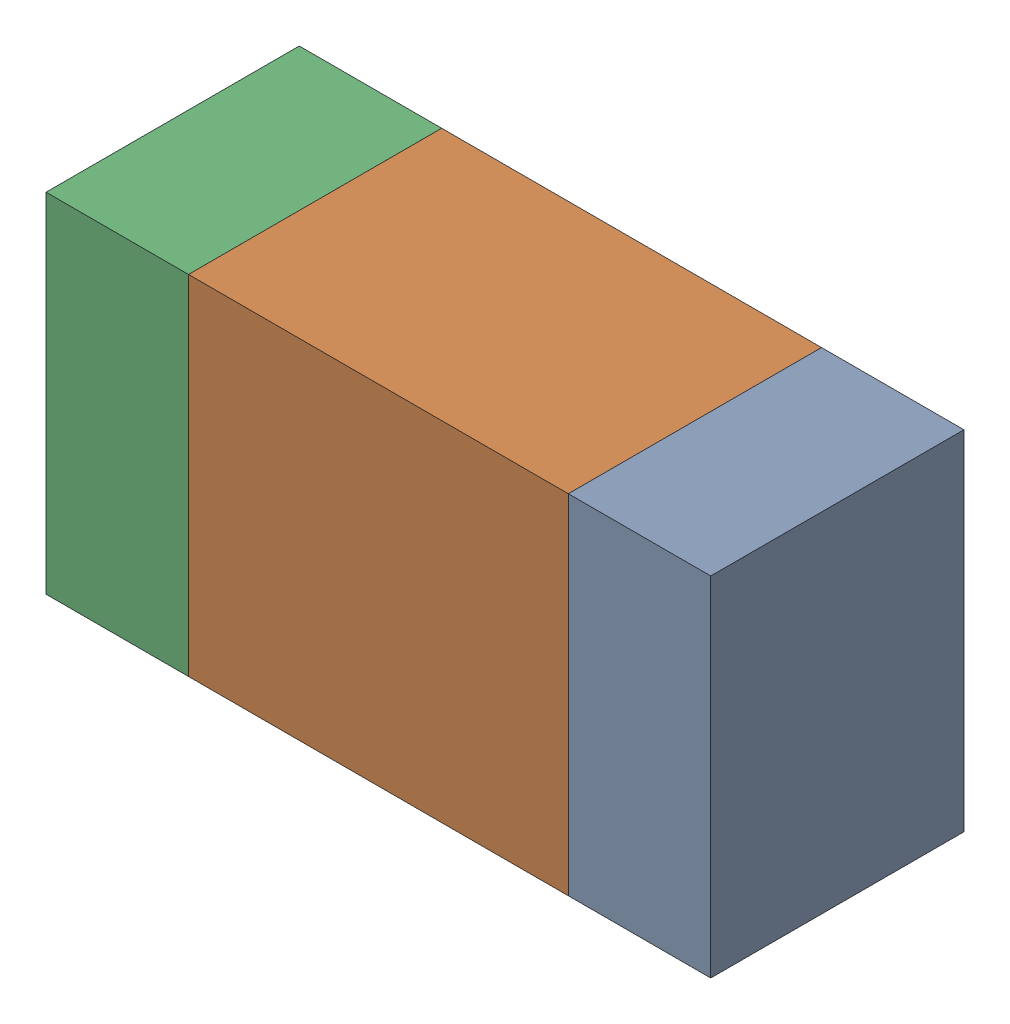
SolidWorks assembly R705PCB, configuration Default. Lengths in mm.
Overall size (1.05 0.55 0.4).
6 component instances, 2 part files, 0 mates.
Components (placement in the parent):
- 854785432-1: 854785432 [Default] at (104.4124 120.5001 -2.0638) size (0.22 0.55 0.4)
  - Extruded-1: Extruded [Default] at origin size (0.22 0.55 0.4)
- 854785568-1: 854785568 [Default] at (103.9999 120.5001 -2.0638) size (0.6 0.55 0.4)
  - Extruded_2-1: Extruded_2 [Default] at origin size (0.6 0.55 0.4)
- 854785432-2: 854785432 [Default] at (103.5874 120.5001 -2.0638) size (0.22 0.55 0.4)
  - Extruded-1: Extruded [Default] at origin size (0.22 0.55 0.4)
